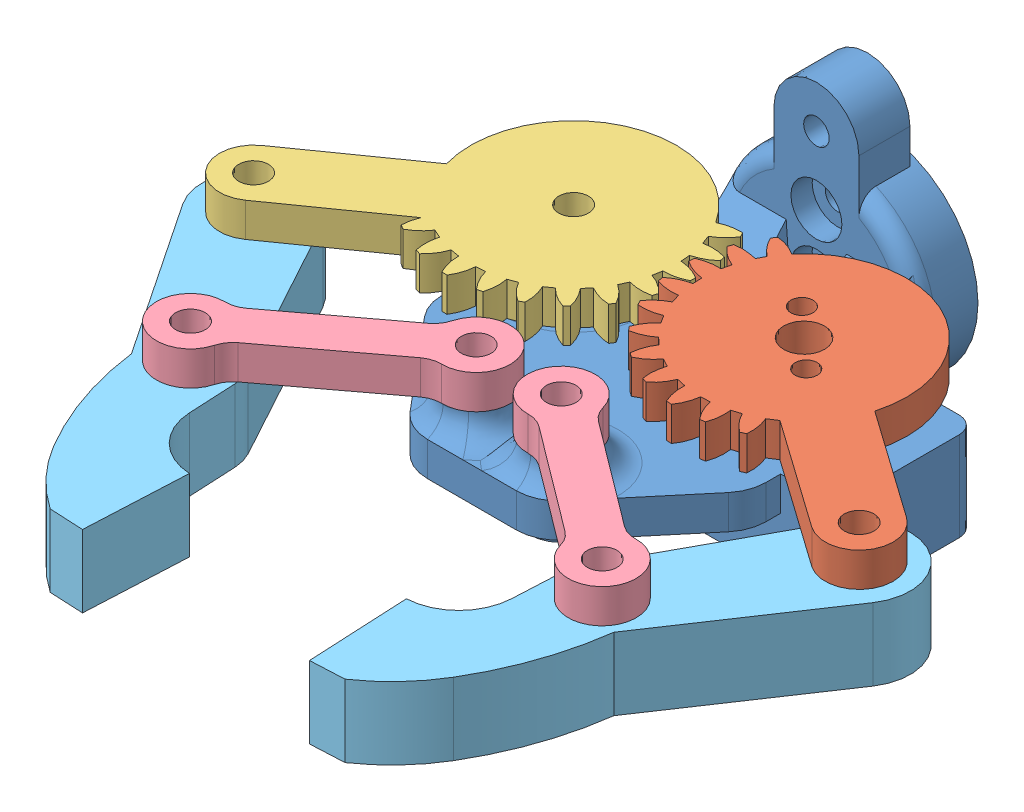
SolidWorks assembly GripperV3, configuration Predeterminado. Lengths in mm.
Overall size (90.21 32 79.95).
7 component instances, 5 part files, 23 mates.
Components (placement in the parent):
- BaseGriper V3-1: BaseGriper V3 [Predeterminado] at (-8.7731 -6.8279 41.0682) size (44.63 32 47.5)
- gear2_r1-1: gear2_r1 [Default] at (-2.6469 0.1721 34.2107) x (-0.734568 0 -0.678535) z (0.678535 0 -0.734568) size (45.31 4 26.63)
- gear1_r1-1: gear1_r1 [Default] at (-30.5784 0.1721 46.898) x (-0.816851 0 0.576849) z (-0.576849 0 -0.816851) size (45.54 4 26.63)
- grip link 1_r1-1: grip link 1_r1 [Default] at (-32.9793 0.1721 75.4599) x (0.80026 0 -0.599653) z (0.599653 0 0.80026) size (32 4 8)
- grip link 1_r1-2: grip link 1_r1 [Default] at (-3.7731 0.1721 61.0682) x (0.80026 0 0.599653) z (-0.599653 0 0.80026) size (32 4 8)
- Dedo-1: Dedo [Predeterminado] at (-21.7246 -8.3279 91.0269) x (0.998812 0 0.048737) z (-0.048737 0 0.998812) size (30.3 8.5 47.24)
- Dedo-2: Dedo [Predeterminado] at (4.1785 0.1721 91.0269) x (-0.998812 0 0.048737) z (0.048737 0 0.998812) size (30.3 8.5 47.24)
Mates (geometry in assembly coordinates):
- Coincidente1: coincident anti-aligned: plane of BaseGriper V3-1 through (-3.7731 0.1721 61.0682) normal (0 1 0); plane of gear2_r1-1 through (-17.811 0.1721 20.2033) normal (0 -1 0)
- Concéntrica2: concentric aligned: cylinder of BaseGriper V3-1 through (-22.3231 -2.8279 41.0682) axis (0 -1 0) radius 1.4; cylinder of gear1_r1-1 through (-22.3231 4.1721 41.0682) axis (0 -1 0) radius 1.75
- Coincidente2: coincident anti-aligned: plane of BaseGriper V3-1 through (-22.5731 0.1721 40.9762) normal (0 1 0); plane of gear1_r1-1 through (-24.9976 0.1721 53.4689) normal (0 -1 0)
- Coincidente3: coincident anti-aligned: plane of BaseGriper V3-1 through (-13.7731 0.1721 61.0682) normal (0 1 0); plane of grip link 1_r1-1 through (-32.9793 0.1721 75.4599) normal (0 -1 0)
- Coincidente4: coincident anti-aligned: plane of BaseGriper V3-1 through (-3.7731 0.1721 61.0682) normal (0 1 0); plane of grip link 1_r1-2 through (-3.7731 0.1721 61.0682) normal (0 -1 0)
- Coincidente9: coincident anti-aligned: plane of gear1_r1-1 through (-24.9976 0.1721 53.4689) normal (0 -1 0); plane of Gripper 1_r1-1 through (-31.9314 0.1721 58.7567) normal (0 1 0)
- Concéntrica6: concentric anti-aligned: cylinder of grip link 1_r1-1 through (-32.9793 4.1721 75.4599) axis (0 -1 0) radius 1.75; cylinder of Gripper 1_r1-1 through (-21.0109 -8.3279 83.9508) axis (0 1 0) radius 1.75
- Concéntrica7: concentric anti-aligned: cylinder of gear2_r1-1 through (26.8319 0.1721 56.6431) axis (0 1 0) radius 1.75; cylinder of Gripper 1_r1-2 through (15.7434 0.1721 65.6961) axis (0 -1 0) radius 1.75
- Coincidente10: coincident anti-aligned: plane of gear2_r1-1 through (-17.811 0.1721 20.2033) normal (0 -1 0); plane of Gripper 1_r1-2 through (14.3852 0.1721 58.7567) normal (0 1 0)
- Concéntrica8: concentric aligned: cylinder of grip link 1_r1-2 through (15.4332 4.1721 75.4599) axis (0 -1 0) radius 1.75; cylinder of Gripper 1_r1-2 through (3.4648 0.1721 83.9508) axis (0 -1 0) radius 1.75
- Concéntrica9: concentric anti-aligned: cylinder of BaseGriper V3-1 through (4.7769 -2.8279 41.0682) axis (0 -1 0) radius 5; cylinder of gear2_r1-1 through (4.7769 0.1711 41.0682) axis (0 1 0) radius 2.4
- Concéntrica10: concentric anti-aligned: cylinder of gear1_r1-1 through (-44.378 4.1721 56.6431) axis (0 -1 0) radius 1.75; cylinder of Gripper 1_r1-1 through (-33.2896 -8.3279 65.6961) axis (0 1 0) radius 1.75
- Concéntrica11: concentric aligned: cylinder of BaseGriper V3-1 through (-13.7731 -2.8279 61.0682) axis (0 -1 0) radius 1.4; cylinder of grip link 1_r1-1 through (-13.7731 4.1721 61.0682) axis (0 -1 0) radius 1.75
- Concéntrica12: concentric aligned: cylinder of BaseGriper V3-1 through (-3.7731 -2.8279 61.0682) axis (0 -1 0) radius 1.4; cylinder of grip link 1_r1-2 through (-3.7731 4.1721 61.0682) axis (0 -1 0) radius 1.75
- Simétrico3: symmetric aligned: plane of BaseGriper V3-1 through (-8.7731 -6.8279 41.0682) normal (1 0 0); plane of Gripper 1_r1-2 through (2.1903 -8.3279 56.3954) normal (-0.981766 0 -0.190096); plane of Gripper 1_r1-1 through (-19.7365 0.1721 56.3954) normal (0.981766 0 -0.190096)
- Coincidente11: coincident anti-aligned: line of Gripper 1_r1-1 through (-8.7731 0.1721 113.0168) axis (0 -1 0); line of Gripper 1_r1-2 through (-8.7731 -8.3279 113.0168) axis (0 1 0)
- Concéntrica13: concentric aligned: cylinder of gear1_r1-1 through (-44.378 4.1721 56.6431) axis (0 -1 0) radius 1.75; cylinder of Dedo-1 through (-44.378 0.1721 56.6431) axis (0 -1 0) radius 1.5
- Concéntrica14: concentric aligned: cylinder of grip link 1_r1-1 through (-32.9793 4.1721 75.4599) axis (0 -1 0) radius 1.75; cylinder of Dedo-1 through (-32.9793 0.1721 75.4599) axis (0 -1 0) radius 1.5
- Concéntrica15: concentric anti-aligned: cylinder of grip link 1_r1-2 through (15.4332 4.1721 75.4599) axis (0 -1 0) radius 1.75; cylinder of Dedo-2 through (15.4332 -8.3279 75.4599) axis (0 1 0) radius 1.5
- Concéntrica16: concentric aligned: cylinder of gear2_r1-1 through (26.8319 0.1721 56.6431) axis (0 1 0) radius 1.75; cylinder of Dedo-2 through (26.8319 -8.3279 56.6431) axis (0 1 0) radius 1.5
- Coincidente12: coincident anti-aligned: plane of gear1_r1-1 through (-24.9976 0.1721 53.4689) normal (0 -1 0); plane of Dedo-1 through (-44.378 0.1721 56.6431) normal (0 1 0)
- Coincidente13: coincident anti-aligned: plane of gear2_r1-1 through (-17.811 0.1721 20.2033) normal (0 -1 0); plane of Dedo-2 through (26.8319 0.1721 56.6431) normal (0 1 0)
- Simétrico4: symmetric aligned: plane of BaseGriper V3-1 through (-8.7731 -6.8279 41.0682) normal (1 0 0); plane of Dedo-2 through (3.9836 -8.3279 87.0316) normal (-0.998812 0 0.048737); plane of Dedo-1 through (-21.5297 0.1721 87.0316) normal (0.998812 0 0.048737)
